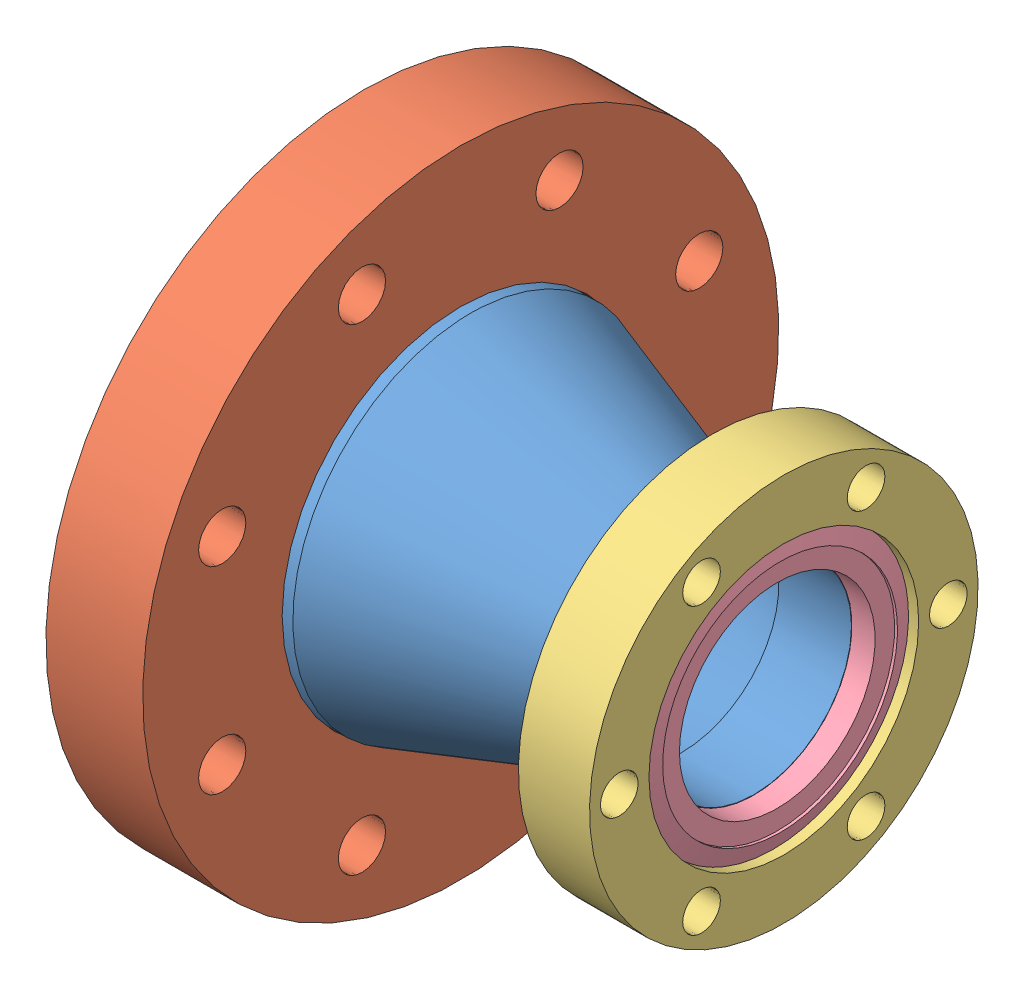
SolidWorks assembly 402032, configuration Default. Lengths in mm.
Overall size (74.93 113.54 113.54).
5 component instances, 4 part files, 0 mates.
Components (placement in the parent):
- 402032-001-1: 402032-001 [Default] at origin size (60.1 63.5 63.5)
- 110021 (4.5 X 2.5 NR)-1: 110021 (4.5 X 2.5 NR) [Default] at (-9.525 0 0) size (17.27 113.54 113.54)
- 100014 (2.75 X 1.5 R)-1: 100014 (2.75 X 1.5 R) [Default] at (65.405 0 0) x (-1 0 0) z (0 0 -1) size (12.7 69.34 69.34)
  - 100014 (2.75 X 1.5 REC)-1: 100014 (2.75 X 1.5 REC) [Default] at origin size (12.7 69.34 69.34)
  - 100014 (2.75 X 1.5 INS)-1: 100014 (2.75 X 1.5 INS) [Default] at (1.17 0 0) x (1 0 0) z (0 0.994423 -0.105464) size (6.96 48.1 48.1)
